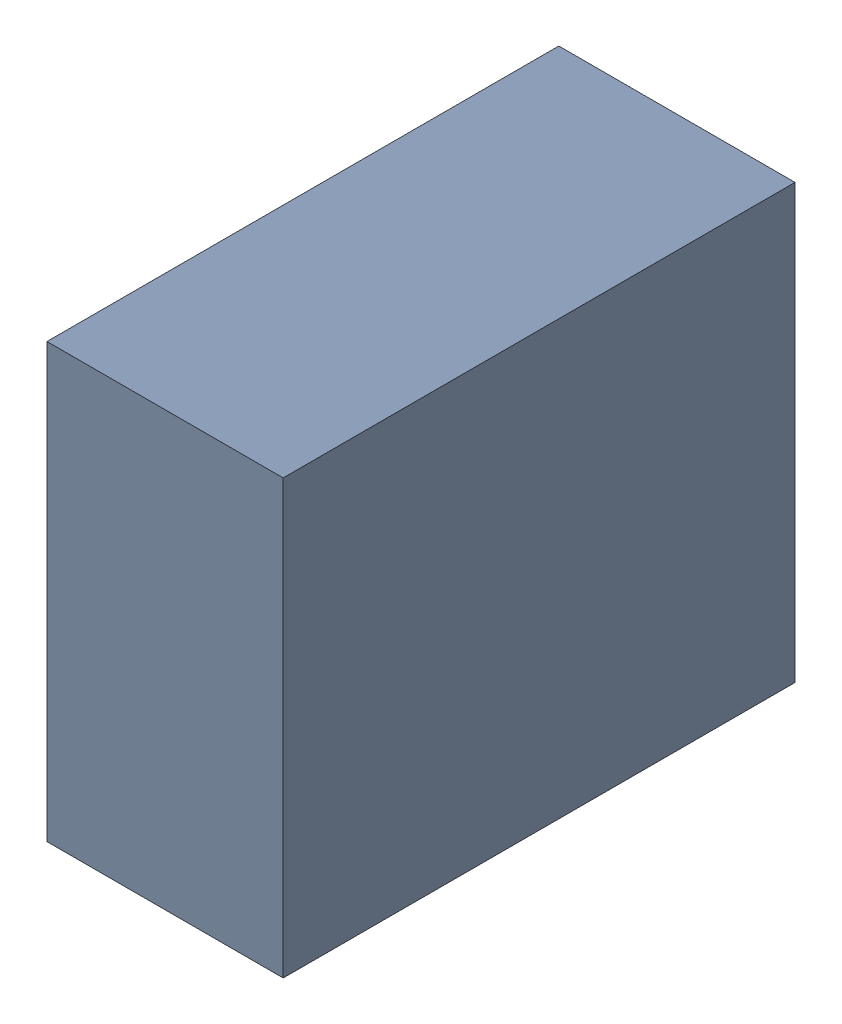
SolidWorks assembly C21_TDA1, configuration Standard. Lengths in mm.
Overall size (0.6 1.1 1.3).
2 component instances, 1 part files, 0 mates.
Components (placement in the parent):
- 885542376-1: 885542376 [Standard] at (-4.92 49.94 0) size (0.6 1.1 1.3)
  - Extruded_25-1: Extruded_25 [Standard] at origin size (0.6 1.1 1.3)
